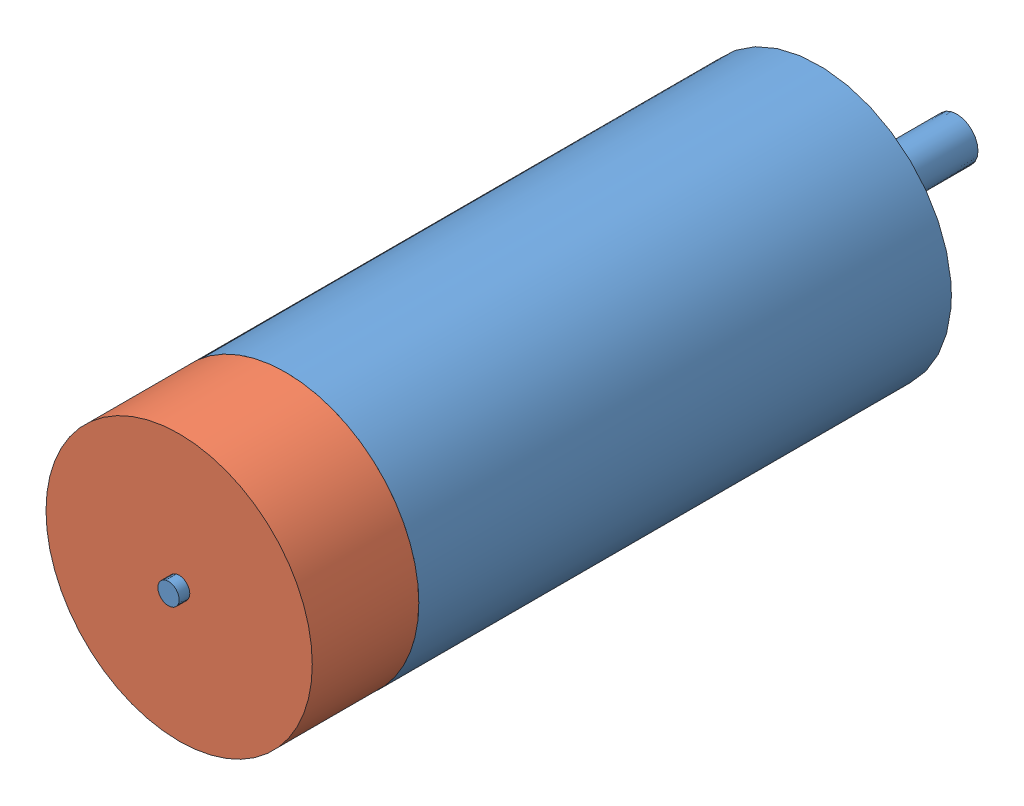
SolidWorks assembly motor with encoder, configuration Default. Lengths in mm.
Overall size (25 25 74).
2 component instances, 2 part files, 2 mates.
Components (placement in the parent):
- motor-1: motor [Default] at (22.9042 35.6027 32.4244) size (25 25 74)
- encoders-1: encoders [Default] at (22.9042 35.6027 82.4244) size (25 25 10)
Mates (geometry in assembly coordinates):
- Coincident2: coincident anti-aligned: plane of motor-1 through (22.9042 35.6027 82.4244) normal (0 0 1); plane of encoders-1 through (22.9042 35.6027 82.4244) normal (0 0 -1)
- Concentric1: concentric aligned: circle of motor-1; circle of encoders-1
